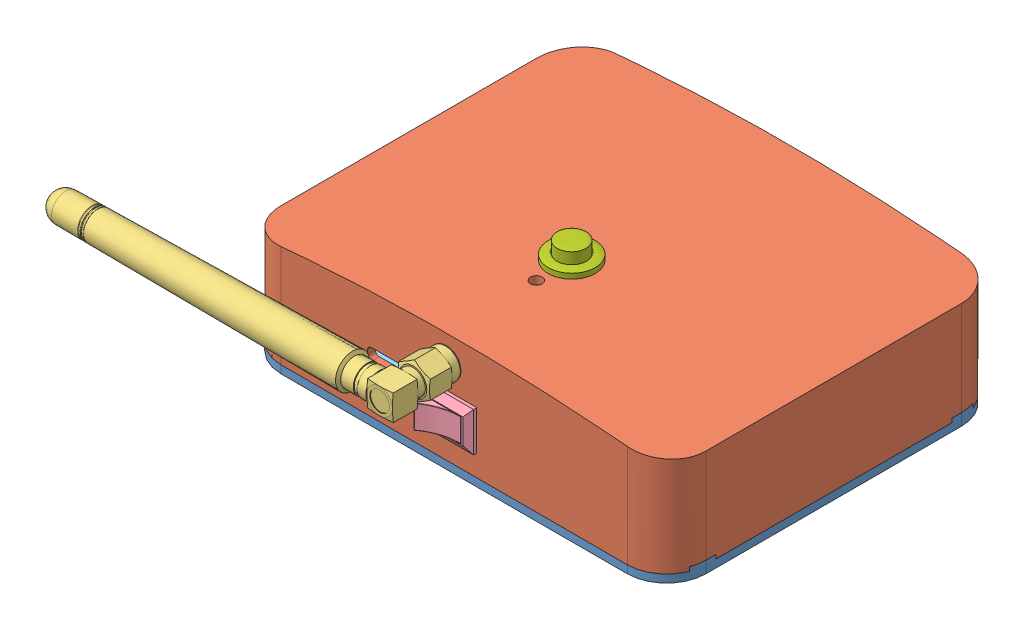
SolidWorks assembly Hub, configuration Default. Lengths in mm.
Overall size (142.63 34.75 103.05).
8 component instances, 7 part files, 19 mates.
Components (placement in the parent):
- Hub_bottom_v2-1: Hub_bottom_v2 [Default] at origin size (108 10.69 85)
- Hub_top_v2-1: Hub_top_v2 [Default] at (0 0 34.0152) size (108 28.27 85)
- Antenna 868  F-1: Antenna 868  F [По умолчанию] at (11.999 23.5 47.7152) x (-0.006213 0.999981 0) z (0 0 1) size (9.24 90.6 18.05)
- Switch on off-1: Switch on off [Default] at (12.24 12.4361 26.0152) x (0 1 0) z (1 0 0) size (10 19.96 15)
- circuit-1: circuit [Default] at (-32.0082 5 27.0118) x (0 0 -1) z (0 1 0) size (72.72 51.79 14.01)
- 18650 Battery Holder v5-1: 18650 Battery Holder v5 [Default] at (28.7632 2 -8.4848) x (1 0 0) z (0 1 0) size (21 75 19.5)
- 18650 Battery Holder v5-2: 18650 Battery Holder v5 [Default] at (49.7632 2 -8.4848) x (1 0 0) z (0 1 0) size (21 75 19.5)
- sw-1: sw [Default] at (11.8847 30.0146 2.0152) x (0.618002 0 -0.786177) z (0 1 0) size (11.94 11.94 27.46)
Mates (geometry in assembly coordinates):
- Concentric1: concentric anti-aligned: circle of Hub_top_v2-1; circle of Antenna 868  F-1
- Coincident4: coincident anti-aligned: plane of Hub_top_v2-1 through (0 44 34.0152) normal (0 0 1); plane of Antenna 868  F-1 through (11.999 23.5 34.0152) normal (0 0 -1)
- Coincident5: coincident aligned: plane of Hub_bottom_v2-1 through (-40.001 2 -40.9848) normal (-1 0 0); plane of Hub_top_v2-1 through (-40.001 44 34.0152) normal (-1 0 0)
- Coincident6: coincident aligned: plane of Hub_bottom_v2-1 through (-30.001 2 34.0152) normal (0 0 1); plane of Hub_top_v2-1 through (0 44 34.0152) normal (0 0 1)
- Coincident7: coincident anti-aligned: plane of Hub_top_v2-1 through (0 44 34.0152) normal (0 0 1); plane of Switch on off-1 through (5.42 16.7011 34.0152) normal (0 0 -1)
- Parallel3: parallel anti-aligned: plane of Hub_top_v2-1 through (0 17 19.0152) normal (0 -1 0); plane of Switch on off-1 through (12.24 17.4361 34.0152) normal (0 1 0)
- Parallel4: parallel aligned: plane of Hub_bottom_v2-1 through (-40.001 2 -40.9848) normal (-1 0 0); plane of circuit-1 through (-31.9955 5 27.7611) normal (-1 0 0)
- Coincident9: coincident anti-aligned: plane of Hub_bottom_v2-1 through (-30.001 2 24.0152) normal (0 1 0); plane of 18650 Battery Holder v5-1 through (28.7632 2 -8.4848) normal (0 -1 0)
- Parallel5: parallel aligned: plane of Hub_bottom_v2-1 through (-30.001 2 34.0152) normal (0 0 1); plane of 18650 Battery Holder v5-1 through (18.2632 2 29.0152) normal (0 0 1)
- Coincident10: coincident anti-aligned: plane of 18650 Battery Holder v5-1 through (39.2632 2 29.0152) normal (1 0 0); plane of 18650 Battery Holder v5-2 through (39.2632 2 -45.9848) normal (-1 0 0)
- Coincident11: coincident anti-aligned: plane of Hub_bottom_v2-1 through (-30.001 2 24.0152) normal (0 1 0); plane of 18650 Battery Holder v5-2 through (49.7632 2 -8.4848) normal (0 -1 0)
- Coincident12: coincident aligned: plane of 18650 Battery Holder v5-1 through (39.2632 2 -45.9848) normal (0 0 -1); plane of 18650 Battery Holder v5-2 through (60.2632 2 -45.9848) normal (0 0 -1)
- Width2: width aligned: plane of circuit-1 through (17.9791 5 27.7611) normal (0 0 1); plane of Hub_bottom_v2-1 through (-31.9955 5 -44.7307) normal (0 0 -1); plane of circuit-1 through (-30.001 2 34.0152) normal (0 0 1); plane of Hub_bottom_v2-1 through (-30.001 2 -50.9848) normal (0 0 -1)
- Width3: width aligned: plane of 18650 Battery Holder v5-1 through (18.2632 2 29.0152) normal (0 0 1); plane of Hub_bottom_v2-1 through (60.2632 2 -45.9848) normal (0 0 -1); plane of 18650 Battery Holder v5-2 through (-30.001 2 34.0152) normal (0 0 1); plane of Hub_bottom_v2-1 through (-30.001 2 -50.9848) normal (0 0 -1)
- Coincident13: coincident aligned: plane of Hub_bottom_v2-1 through (-7.0082 6.6 -8.4848) normal (0 1 0); plane of circuit-1 through (-7.0082 6.6 -8.4848) normal (0 1 0)
- Parallel6: parallel aligned: plane of Hub_top_v2-1 through (0 2 34.0152) normal (0 -1 0); plane of sw-1 through (11.8847 21.6146 2.0152) normal (0 -1 0)
- Tangent2: tangent: curve of Hub_top_v2-1; plane of sw-1 through (11.8847 30.0146 2.0152) normal (0 -1 0)
- Coincident16: coincident anti-aligned: plane of Hub_bottom_v2-1 through (-30.001 2 24.0152) normal (0 1 0); plane of Hub_top_v2-1 through (0 2 34.0152) normal (0 -1 0)
- Concentric4: concentric aligned: cylinder of Hub_top_v2-1 through (11.8847 44 2.0152) axis (0 -1 0) radius 4.5284; cone of sw-1 through (11.8847 28.4146 2.0152) axis (0 -1 0)
